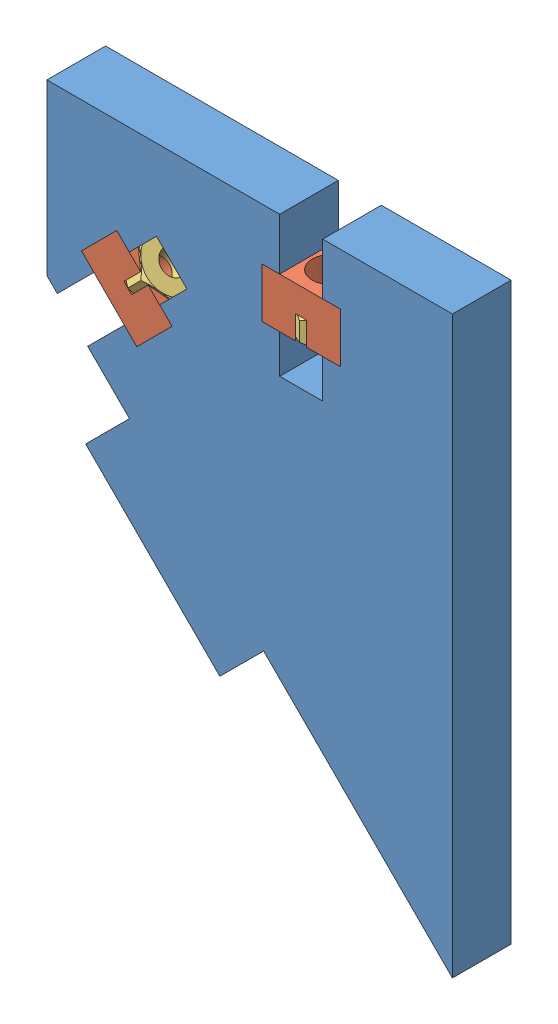
SolidWorks assembly Montagem7, configuration Valor predeterminado. Lengths in mm.
Overall size (41.47 58.8 7.94).
7 component instances, 3 part files, 6 mates.
Components (placement in the parent):
- lcd-support-a-1: lcd-support-a [Valor predeterminado] at (-53.685 -41.6036 55.8) size (41.47 58.8 6)
- Assembly m3-nut-adapter + Nut DIN 934 - M3-1: Assembly m3-nut-adapter + Nut DIN 934 - M3 [Valor predeterminado] at (-17.1729 9.694 58.8) x (0.707107 -0.707107 0) z (0.707107 0.707107 0) size (8.25 7.94 5.1)
  - m3-nut-adapter-1: m3-nut-adapter [Valor predeterminado] at origin size (8 6 5.1)
  - Nut DIN 934 - M3-1: Nut DIN 934 - M3 [Valor predeterminado] at (0 0 3.9) x (0 0 1) z (-0.866025 -0.5 0) size (2.4 5.5 6.35)
- Assembly m3-nut-adapter + Nut DIN 934 - M3-2: Assembly m3-nut-adapter + Nut DIN 934 - M3 [Valor predeterminado] at (2.4631 20.5957 58.8) x (1 0 0) z (0 -1 0) size (8.25 7.94 5.1)
  - m3-nut-adapter-1: m3-nut-adapter [Valor predeterminado] at origin size (8 6 5.1)
  - Nut DIN 934 - M3-1: Nut DIN 934 - M3 [Valor predeterminado] at (0 0 3.9) x (0 0 1) z (-0.866025 -0.5 0) size (2.4 5.5 6.35)
Mates (geometry in assembly coordinates):
- Coincidente1: coincident: plane of assembly; plane of assembly; plane of lcd-support-a-1 through (-53.685 -41.6036 61.8) normal (0 0 1); plane of Assembly m3-nut-adapter + Nut DIN 934 - M3-1/m3-nut-adapter-1 through (-16.3951 16.1287 61.8) normal (0 0 1)
- Coincidente2: coincident: plane of assembly; plane of assembly; plane of lcd-support-a-1 through (-20.0013 12.5224 61.8) normal (0.707107 -0.707107 0); plane of Assembly m3-nut-adapter + Nut DIN 934 - M3-1/m3-nut-adapter-1 through (-16.3951 16.1287 55.8) normal (-0.707107 0.707107 0)
- Coincidente3: coincident: plane of assembly; plane of assembly; plane of lcd-support-a-1 through (-14.3445 6.8656 61.8) normal (0.707107 0.707107 0); plane of Assembly m3-nut-adapter + Nut DIN 934 - M3-1/m3-nut-adapter-1 through (-17.1729 9.694 58.8) normal (-0.707107 -0.707107 0)
- Coincidente4: coincident: plane of assembly; plane of assembly; plane of lcd-support-a-1 through (-1.5369 20.5957 61.8) normal (0 -1 0); plane of Assembly m3-nut-adapter + Nut DIN 934 - M3-2/m3-nut-adapter-1 through (2.4631 20.5957 58.8) normal (0 1 0)
- Coincidente5: coincident: plane of assembly; plane of assembly; plane of lcd-support-a-1 through (-53.685 -41.6036 61.8) normal (0 0 1); plane of Assembly m3-nut-adapter + Nut DIN 934 - M3-2/m3-nut-adapter-1 through (-1.5369 15.4957 61.8) normal (0 0 1)
- Coincidente6: coincident: plane of assembly; plane of assembly; plane of lcd-support-a-1 through (6.4631 20.5957 61.8) normal (-1 0 0); plane of Assembly m3-nut-adapter + Nut DIN 934 - M3-2/m3-nut-adapter-1 through (6.4631 15.4957 61.8) normal (1 0 0)
